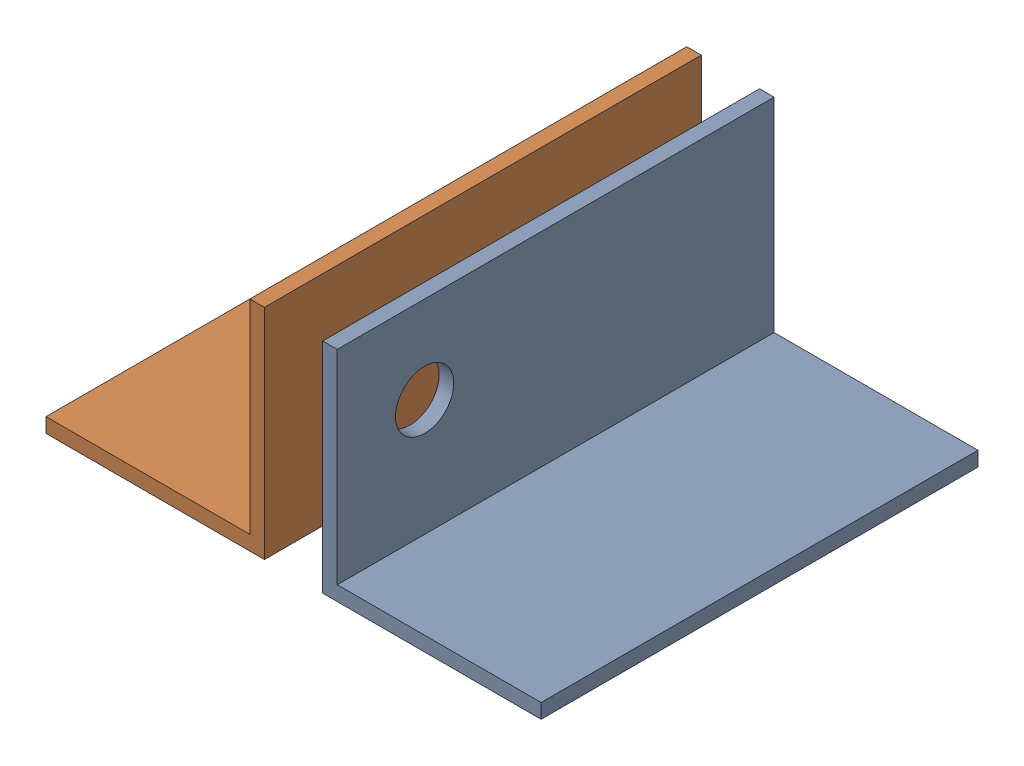
SolidWorks assembly ПроушинаСб, configuration По умолчанию. Lengths in mm.
Overall size (170 75 150).
2 component instances, 2 part files, 6 mates.
Components (placement in the parent):
- ПроушинаЛ-1: ПроушинаЛ [По умолчанию] at (10 0 -150) x (1 0 0) z (0 -1 0) size (75 150 75)
- ПроушинаП-1: ПроушинаП [По умолчанию] at (-10 0 -150) x (0 1 0) z (1 0 0) size (75 150 75)
Mates (geometry in assembly coordinates):
- Совпадение1: coincident anti-aligned: plane of ПроушинаП-1 through (-85 0 0) normal (0 -1 0)
- Совпадение2: coincident aligned: plane of ПроушинаП-1 through (-10 0 0) normal (0 0 1)
- Расстояние1: distance = 10 mm: plane of assembly; point of assembly; plane of ПроушинаП-1 through (-10 0 0) normal (1 0 0)
- Совпадение4: coincident aligned: plane of ПроушинаЛ-1 through (39.3424 0 0) normal (0 0 1); plane of ПроушинаП-1 through (-10 0 0) normal (0 0 1)
- Концентричный1: concentric anti-aligned: cylinder of ПроушинаЛ-1 through (114.3424 45 -30) axis (-1 0 0) radius 10; cylinder of ПроушинаП-1 through (-85 45 -30) axis (1 0 0) radius 10
- Расстояние2: distance = 10 mm: plane of assembly; point of assembly; plane of ПроушинаЛ-1 through (10 75 0) normal (-1 0 0)
